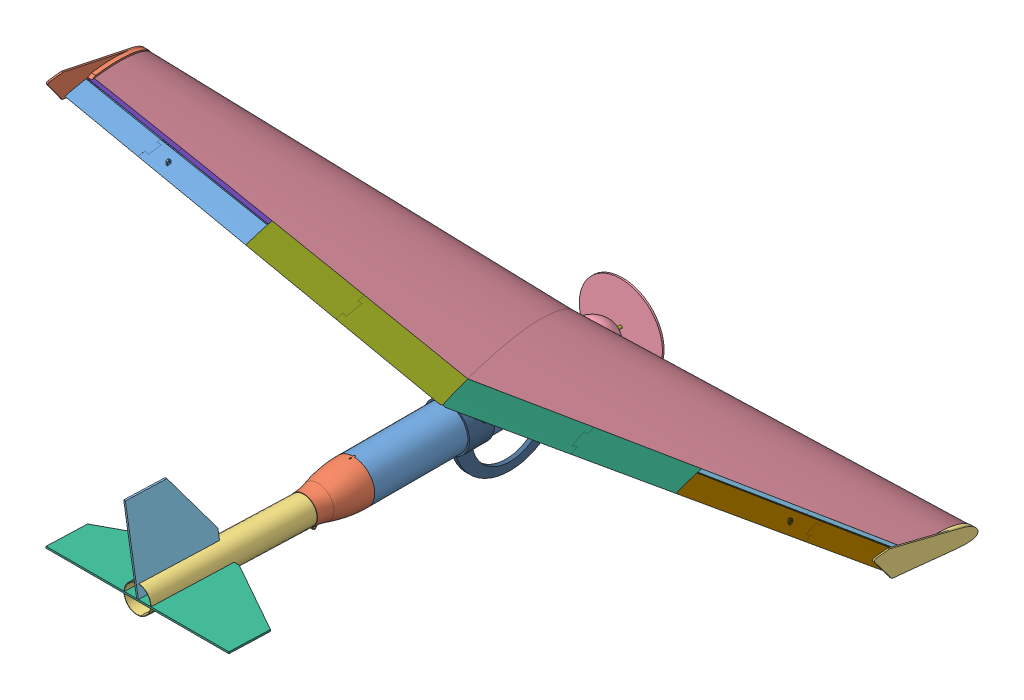
SolidWorks assembly Assembly, configuration Default. Lengths in mm.
Overall size (1273.36 257.1 765.83).
24 component instances, 22 part files, 38 mates.
Components (placement in the parent):
- Main fuselage-1: Main fuselage [Default] at origin size (64.77 64.77 355.6)
- Fuselage adapter-1: Fuselage adapter [Default] at (0 0 330.2) size (64.9 64.92 168.91)
- Rear fuselage-1: Rear fuselage [Default] at (0 -2.6593 355.6464) x (1 0 0) z (0 0.034899 0.999391) size (41.27 41.27 330.2)
- Motor mount-1: Motor mount [Default] at (0 0 -4.7625) size (64.77 64.77 176.21)
- Vertical stabilizer-1: Vertical stabilizer [Default] at (0 8.8645 685.6453) x (1 0 0) z (0 0.034899 0.999391) size (2.54 139.7 151.63)
- Horizontal stabilizer-1: Horizontal stabilizer [Default] at (0 6.326 685.7339) x (1 0 0) z (0 0.034899 0.999391) size (279.4 2.54 127)
- Motor-1: Motor [Default] at (0 0 -4.7625) x (-0.36337 0.931645 0) z (0 0 1) size (27.94 27.94 50.8)
- Battery-1: Battery [Default] at (0 -14.5128 12.8701) x (0 0 1) z (-1 0 0) size (146.05 25.4 50.8)
- servo-1: servo [Default] at (0.127 -26.035 312.42) x (0 0 1) z (-1 0 0) size (32.26 30 31.75)
- servo-2: servo [Default] at (0.127 -20.955 279.4) x (0 0 1) z (-1 0 0) size (32.26 30 31.75)
- Wing mount-1: Wing mount [Default] at (0 49.53 60.7589) x (0 -0.104528 0.994522) z (-1 0 0) size (185.86 150.15 102.47)
- Receiver-1: Receiver [Default] at (13.0555 12.6652 38.1) x (0 0 1) z (-1 0 0) size (47 14.99 26.2)
- Esc-1: Esc [Default] at (-12.5 -27.2908 94.0631) x (0 0 -1) z (1 0 0) size (53 11 25)
- Wing Assem-1: Wing Assem [Default] at (0 50.091 57.4316) x (0 -0.113068 0.993587) z (-1 0 0) size (211.68 111.64 1273.36)
  - NACA_4415 Wing 2-1: NACA_4415 Wing 2 [Default] at origin size (177.81 79.2 1266.82)
  - R Fairing-1: R Fairing [Default] at origin size (35.51 36.3 304.73)
  - R Trailing edge-1: R Trailing edge [Default] at origin size (74.35 41.39 334.61)
  - L Trailing edge-1: L Trailing edge [Default] at origin size (74.35 41.39 334.61)
  - L Fairing-1: L Fairing [Default] at origin size (35.51 36.3 304.73)
  - R Aileron-1: R Aileron [Default] at origin size (67.3 35.69 304.76)
  - L Aileron-2: L Aileron [Default] at origin size (67.3 35.69 304.76)
  - Winglet L-1: Winglet L [Default] at origin size (150.86 62.09 14.36)
  - Winglet R-1: Winglet R [Default] at origin size (150.86 62.09 14.36)
- Prop^Assembly-1: Prop^Assembly [Default] at origin size (127 127 2.54) (virtual)
Mates (geometry in assembly coordinates):
- Concentric1: concentric anti-aligned: cylinder of Main fuselage-1 through (0 0 355.6) axis (0 0 -1) radius 31.75; cylinder of Fuselage adapter-1 through (0 0 432.092) axis (0 0 1) radius 31.6865
- Parallel1: parallel aligned: plane of Fuselage adapter-1 through (0 30.48 330.2) normal (0 1 0); plane of assembly through (0 0 0) normal (0 1 0)
- Concentric2: concentric anti-aligned: cylinder of Fuselage adapter-1 through (0 -3.5832 329.192) axis (0 0.034899 0.999391) radius 20.6375; cylinder of Rear fuselage-1 through (0 8.8645 685.6453) axis (0 -0.034899 -0.999391) radius 20.1295
- Concentric3: concentric anti-aligned: cylinder of Main fuselage-1 through (0 0 355.6) axis (0 0 -1) radius 31.75; cylinder of Motor mount-1 through (0 0 39.2723) axis (0 0 1) radius 31.6865
- Coincident3: coincident anti-aligned: plane of Main fuselage-1 through (0 0 0) normal (0 0 -1); plane of Motor mount-1 through (0 0 0) normal (0 0 1)
- Coincident4: coincident aligned: plane of Fuselage adapter-1 through (0 0 330.2) normal (0 1 0); plane of Motor mount-1 through (0 0 -4.7625) normal (0 1 0)
- Coincident7: coincident aligned: plane of Vertical stabilizer-1 through (0 8.8645 685.6453) normal (1 0 0); plane of assembly through (0 0 0) normal (1 0 0)
- Coincident8: coincident aligned: plane of Horizontal stabilizer-1 through (0 6.326 685.7339) normal (1 0 0); plane of assembly through (0 0 0) normal (1 0 0)
- Coincident9: coincident anti-aligned: plane of Vertical stabilizer-1 through (-1.27 8.8645 685.6453) normal (0 -0.999391 0.034899); plane of Horizontal stabilizer-1 through (0 8.8645 685.6453) normal (0 0.999391 -0.034899)
- Coincident10: coincident: line of Vertical stabilizer-1 through (-1.27 4.4322 558.7226) axis (1 0 0); plane of Horizontal stabilizer-1 through (28.575 4.4322 558.7226) normal (0 -0.034899 -0.999391)
- Coincident15: coincident anti-aligned: plane of Main fuselage-1 through (0 0 355.6) normal (0 0 1); plane of Fuselage adapter-1 through (0 31.6865 355.6) normal (0 0 -1)
- Distance1: distance = 76.2 mm anti-aligned: plane of Fuselage adapter-1 through (0 3.5436 431.6763) normal (0 0.034899 0.999391); plane of Rear fuselage-1 through (0 -2.6593 355.6464) normal (0 -0.034899 -0.999391)
- Concentric4: concentric aligned: cylinder of Motor mount-1 through (0 0 14.2724) axis (0 0 1) radius 15.24; cylinder of Motor-1 through (0 0 43.9701) axis (0 0 1) radius 13.97
- Coincident28: coincident aligned: circle of Motor mount-1; plane of Motor-1 through (0 0 -4.7625) normal (0 0 1)
- Coincident29: coincident anti-aligned: plane of Battery-1 through (0 -14.5128 12.8701) normal (-1 0 0); plane of assembly through (0 0 0) normal (1 0 0)
- Coincident46: coincident anti-aligned: plane of Fuselage adapter-1 through (-6.35 -32.4495 300.99) normal (0 0 1); plane of servo-1 through (6.35 -3.635 300.99) normal (0 0 -1)
- Coincident47: coincident anti-aligned: plane of Fuselage adapter-1 through (0 -10.16 330.2) normal (0 1 0); plane of servo-1 through (11.6916 -10.16 296.291) normal (0 -1 0)
- Coincident48: coincident aligned: plane of Fuselage adapter-1 through (6.35 -32.4495 295.91) normal (1 0 0); plane of servo-1 through (6.35 -3.635 300.99) normal (1 0 0)
- Coincident49: coincident anti-aligned: plane of Fuselage adapter-1 through (-6.35 -32.4495 267.97) normal (0 0 1); plane of servo-2 through (6.35 1.445 267.97) normal (0 0 -1)
- Coincident50: coincident anti-aligned: plane of Fuselage adapter-1 through (0 -5.08 330.2) normal (0 1 0); plane of servo-2 through (11.6916 -5.08 263.271) normal (0 -1 0)
- Coincident51: coincident aligned: plane of Fuselage adapter-1 through (6.35 -32.4495 262.89) normal (1 0 0); plane of servo-2 through (6.35 1.445 267.97) normal (1 0 0)
- Concentric8: concentric aligned: cylinder of Main fuselage-1 through (0 0 355.6) axis (0 0 -1) radius 32.385; cylinder of Wing mount-1 through (0 0 73.4589) axis (0 0 -1) radius 31.75
- Parallel7: parallel: line of Wing mount-1 through (-41.91 49.53 60.7589) axis (1 0 0); plane of assembly
- Parallel8: parallel aligned: plane of Battery-1 through (-25.4 10.8872 12.8701) normal (-1 0 0); plane of Receiver-1 through (-13.1445 23.3332 38.1) normal (-1 0 0)
- Parallel9: parallel anti-aligned: plane of Battery-1 through (-25.4 10.8872 12.8701) normal (-1 0 0); plane of Esc-1 through (12.5 -16.2908 94.0631) normal (1 0 0)
- Coincident61: coincident: moEndPointRef_w of Esc-1; plane of assembly
- Coincident63: coincident anti-aligned: plane of Motor mount-1 through (-25.4 10.8872 10.16) normal (0 -1 0); plane of Battery-1 through (0 10.8872 12.8701) normal (0 1 0)
- Coincident65: coincident anti-aligned: plane of Motor mount-1 through (-13.1445 23.3332 78.74) normal (1 0 0); plane of Receiver-1 through (-13.1445 23.3332 38.1) normal (-1 0 0)
- Coincident69: coincident anti-aligned: plane of ? through (0 50.091 57.4316) normal (-1 0 0); plane of assembly through (0 0 0) normal (1 0 0)
- Coincident72: coincident: point of Wing mount-1; face of Wing Assem-1/NACA_4415 Wing 2-1
- Coincident73: coincident anti-aligned: plane of Motor mount-1 through (-27.178 12.6652 10.16) normal (0 1 0); plane of Receiver-1 through (13.0555 12.6652 38.1) normal (0 -1 0)
- Coincident75: coincident aligned: plane of Rear fuselage-1 through (0 -2.6593 355.6464) normal (0 0.999391 -0.034899); plane of Horizontal stabilizer-1 through (0 8.8645 685.6453) normal (0 0.999391 -0.034899)
- Coincident76: coincident: plane of Rear fuselage-1 through (0 8.8645 685.6453) normal (0 0.034899 0.999391); line of Horizontal stabilizer-1 through (-139.7 8.8645 685.6453) axis (1 0 0)
- Coincident77: coincident: unknown of Wing mount-1; edge_curve of ?
- Coincident78: coincident anti-aligned: plane of Motor mount-1 through (-1.5875 16.4752 38.1) normal (0 0 1); plane of Receiver-1 through (13.0555 23.3332 38.1) normal (0 0 -1)
- Coincident79: coincident anti-aligned: plane of Motor mount-1 through (-27.178 -16.2908 10.16) normal (0 -1 0); plane of Esc-1 through (-12.5 -16.2908 94.0631) normal (0 1 0)
- Coincident80: coincident: point of Motor mount-1; plane of Esc-1 through (-12.5 -16.2908 94.0631) normal (0 0 1)
- Coincident81: coincident: line of Motor mount-1 through (21.59 -13.8778 12.8701) axis (-1 0 0); plane of Battery-1 through (25.4 10.8872 12.8701) normal (0 0 -1)
